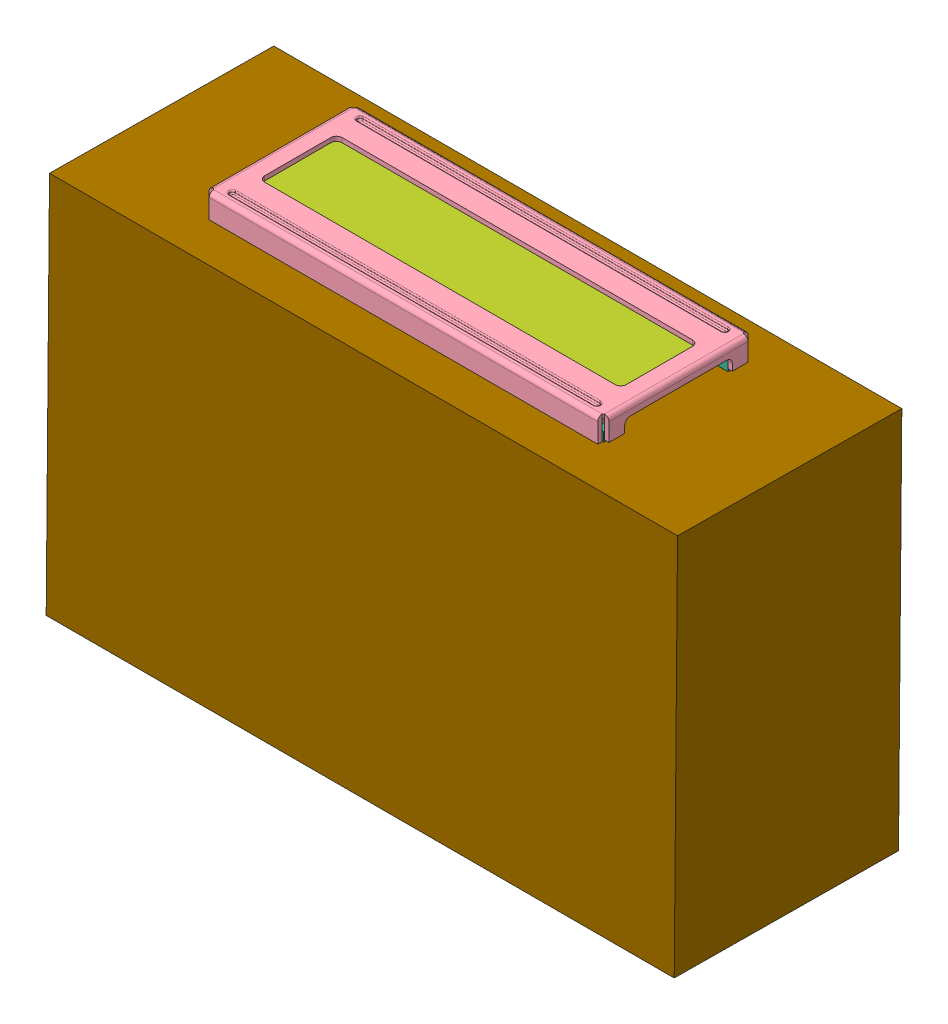
SolidWorks assembly LCD - AP203.STEP, configuration Default. Lengths in mm.
Overall size (112 140.22 40.59).
18 component instances, 11 part files, 0 mates.
Components (placement in the parent):
- i2c board.STEP-1: i2c board.STEP [Default] at (6.1 -5 -15.5) x (-1 0 0) z (0 0 1) size (40.64 1.8 19.35)
- pcbboard.STEP-1: pcbboard.STEP [Default] at origin size (80 4.19 36)
- 16pin_header__.STEP-1: 16pin_header__.STEP [Default] at (-32 0 -15.5) x (0 0 1) z (1 0 0) size (2.54 11.5 40.64)
- lcd window.STEP-1: lcd window.STEP [Default] at (0 9 1.5) size (71.3 11.8 27.44)
- backlight.STEP-1: backlight.STEP [Default] at (0 1.7 1.5) x (-1 0 0) z (0 0 -1) size (74.38 2.98 18)
- conductor.STEP-1: conductor.STEP [Default] at (0 1.7 12.6) size (69.7 5.5 3)
- conductor.STEP-2: conductor.STEP [Default] at (0 1.7 -9.6) size (69.7 5.5 3)
- liquid crystal grabcad i2s.STEP-1: liquid crystal grabcad i2s.STEP [Default] at (0 7.9 1.5) size (68.5 2.2 25)
- smt_resistor222.x_t-1: smt_resistor222.x_t [Default] at (-32.75 0 -5.25) x (0 0 1) z (1 0 0)
- smt_resistor222.x_t-2: smt_resistor222.x_t [Default] at (-32.75 0 -2.75) x (0 0 1) z (1 0 0)
- smt_resistor222.x_t-3: smt_resistor222.x_t [Default] at (-32.75 0 -0.25) x (0 0 1) z (1 0 0)
- smt_resistor222.x_t-4: smt_resistor222.x_t [Default] at (-32.75 0 2.25) x (0 0 1) z (1 0 0)
- smt_resistor222.x_t-5: smt_resistor222.x_t [Default] at (-32.75 0 4.75) x (0 0 1) z (1 0 0)
- smt_resistor222.x_t-6: smt_resistor222.x_t [Default] at (-32.75 0 7.25) x (0 0 1) z (1 0 0)
- smt_resistor101.STEP-1: smt_resistor101.STEP [Default] at (30.25 0 6.1) x (0 0 -1) z (-1 0 0) size (1.8 0.6 5.2)
- smt_resistor101.STEP-2: smt_resistor101.STEP [Default] at (30.25 0 2.85) x (0 0 -1) z (-1 0 0) size (1.8 0.6 5.2)
- Eclosure-1: Eclosure [Default] at (-0.0229 -28.3974 22.2977) x (1 0 0) z (0 0.999962 -0.008727) size (112 40 68)
- PCB1-1: PCB1 [Default] at (79.7998 -130.1619 16.9321) x (-1 0 0) z (0 -0.008727 -0.999962) size (103.49 128.7 35)
